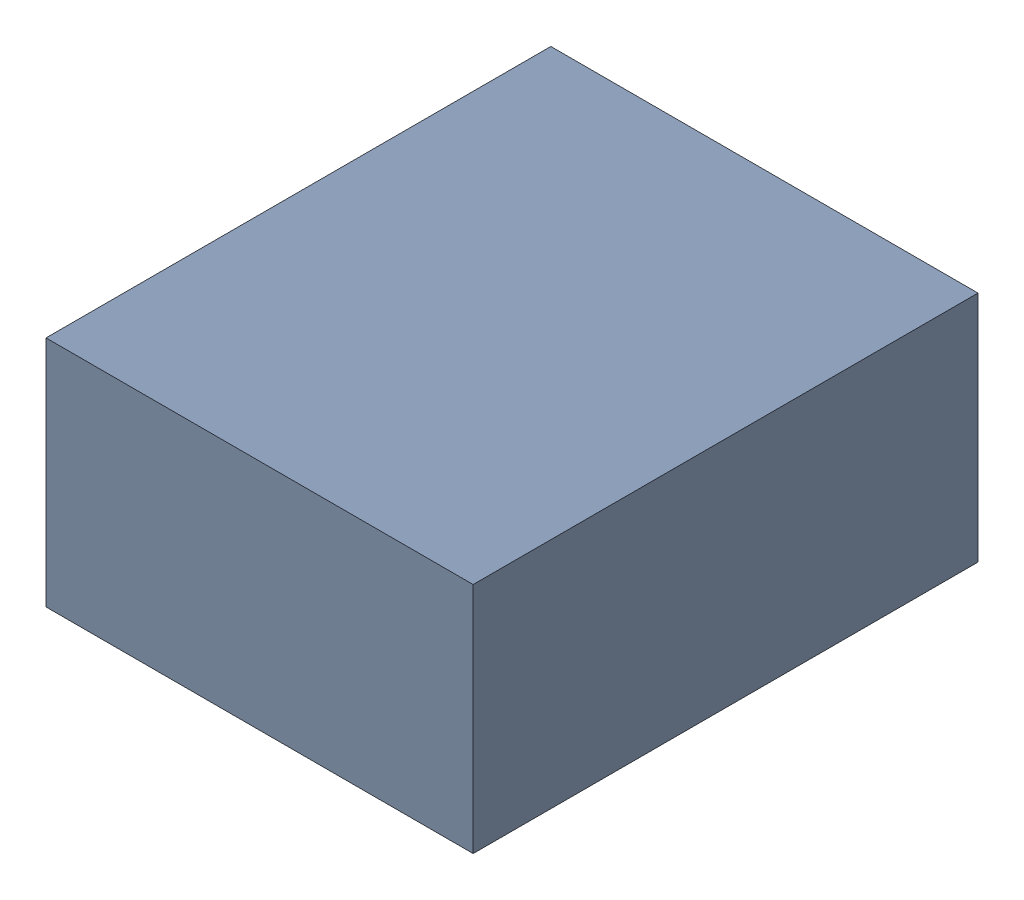
SolidWorks assembly C24_TDA4, configuration Standard. Lengths in mm.
Overall size (1.1 0.6 1.3).
2 component instances, 1 part files, 0 mates.
Components (placement in the parent):
- 885542240-1: 885542240 [Standard] at (0.88 -44.69 0) size (1.1 0.6 1.3)
  - Extruded_28-1: Extruded_28 [Standard] at origin size (1.1 0.6 1.3)
